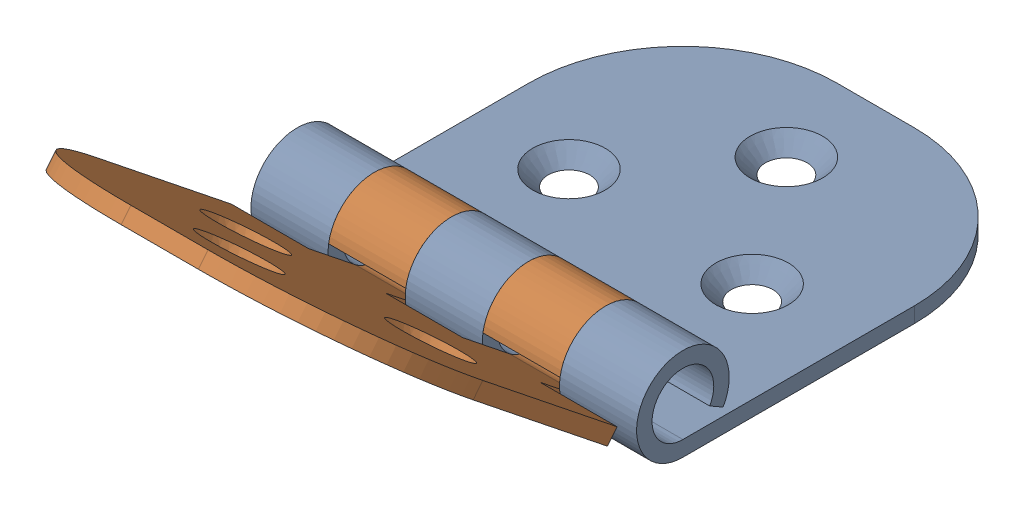
SolidWorks assembly HingeAssembly, configuration Default. Lengths in mm.
Overall size (50 44.32 92.81).
2 component instances, 2 part files, 4 mates.
Components (placement in the parent):
- Hinge-1-1: Hinge-1 [Default] at (25 -6 -50) x (0 1 0) z (1 0 0) size (12 56 50)
- Hinge-2-1: Hinge-2 [Default] at (25 26.5158 42.8125) x (0 0.781361 -0.624079) z (-1 0 0) size (12 56 50)
Mates (geometry in assembly coordinates):
- Hinge2: hinge = 0.673952 rad anti-aligned: cylinder of Hinge-1-1 through (50 0 0) axis (-1 0 0) radius 4; cylinder of Hinge-1-1 through (0 0 0) axis (1 0 0) radius 4; plane of Hinge-2-1 through (40 6 13.0451) normal (-1 0 0); plane of Hinge-2-1 through (40 -2.2033 -12.3727) normal (1 0 0); plane of Hinge-1-1 through (50 -4 0) normal (0 1 0); plane of Hinge-2-1 through (0 -3.1254 2.4963) normal (0 0.781361 -0.624079)
- Concentric2: concentric anti-aligned: cylinder of Hinge-1-1 through (50 0 0) axis (-1 0 0) radius 4
- Coincident1: coincident anti-aligned: plane of Hinge-1-1 through (0 0 0) normal (-1 0 0)
- Parallel1: parallel aligned: plane of Hinge-1-1 through (50 -4 0) normal (0 1 0)
